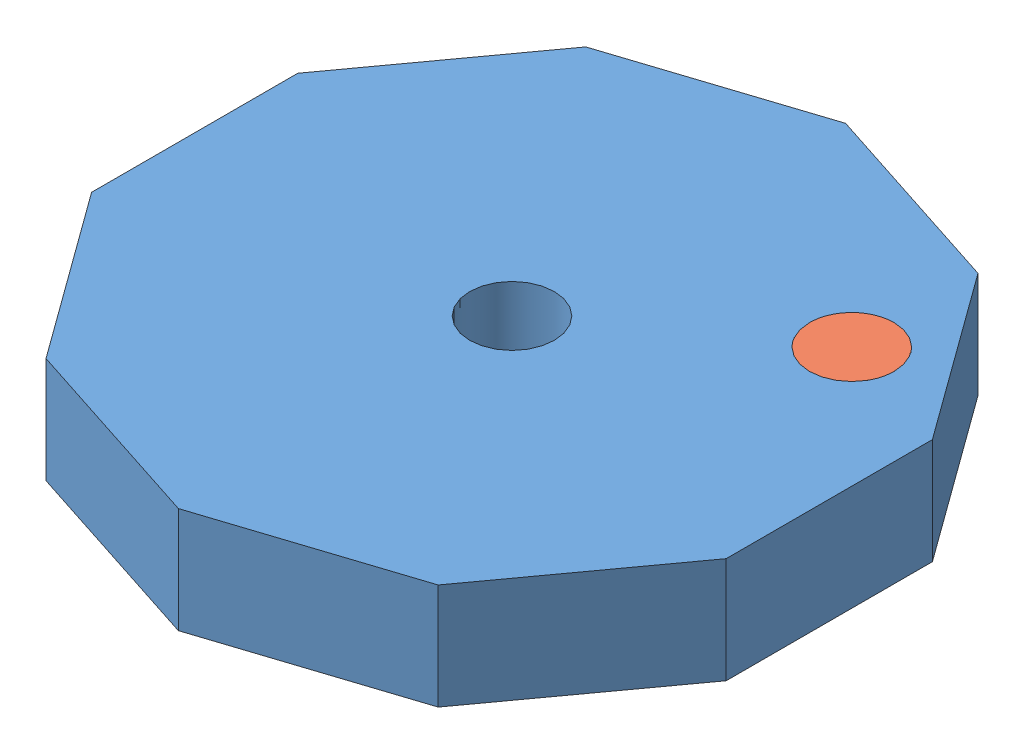
SolidWorks assembly Middle with Conductive, configuration Default. Lengths in mm.
Overall size (30 5 31.54).
2 component instances, 2 part files, 4 mates.
Components (placement in the parent):
- Roatating Middle-1: Roatating Middle [Default] at (6.059 9.6122 18.012) size (30 5 31.54)
- top conductuve-1: top conductuve [Default] at (15.3627 9.6122 11.2524) size (4 5 4)
Mates (geometry in assembly coordinates):
- Concentric1: concentric: cylinder of Roatating Middle-1 through (11.3176 9.6122 14.1914) axis (0 1 0) radius 1.5; cylinder of Conductive Part-1 through (11.3176 14.6122 14.1914) axis (0 -1 0) radius 1.5
- Coincident1: coincident aligned: plane of Roatating Middle-1 through (6.059 14.6122 18.012) normal (0 1 0); plane of Conductive Part-1 through (11.3176 14.6122 14.1914) normal (0 1 0)
- Coincident2: coincident aligned: plane of Roatating Middle-1 through (6.059 9.6122 18.012) normal (0 -1 0); plane of top conductuve-1 through (15.3627 9.6122 11.2524) normal (0 -1 0)
- Concentric2: concentric anti-aligned: cylinder of Roatating Middle-1 through (15.3627 9.6122 11.2524) axis (0 1 0) radius 2; cylinder of top conductuve-1 through (15.3627 14.6122 11.2524) axis (0 -1 0) radius 2
